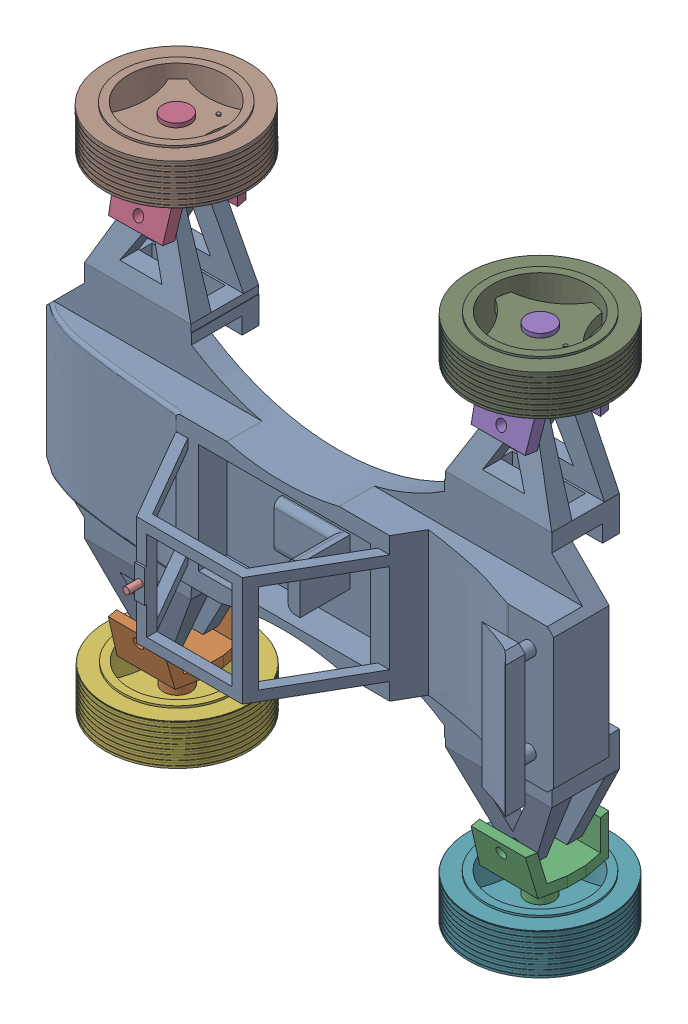
SolidWorks assembly car1, configuration Default. Lengths in mm.
Overall size (815.36 782.99 418.99).
10 component instances, 4 part files, 18 mates.
Components (placement in the parent):
- base-1: base [Default] at origin size (801.15 580 293)
- knuckle1-1: knuckle1 [Default] at (-218.0351 -285.881 -34.5) x (-0.999998 0.001925 0) z (0 0 1) size (100 120 120.94)
- knuckle1-2: knuckle1 [Default] at (317.973 -285.9418 -34.5) x (-0.999995 0.003142 0) z (0 0 1) size (100 120 120.94)
- knuckle1-3: knuckle1 [Default] at (-318.1763 285.0877 -34.5) x (0.999903 0.013919 0) z (0 0 1) size (100 120 120.94)
- knuckle1-4: knuckle1 [Default] at (218.0362 285.8852 -34.5) x (0.999998 -0.002009 0) z (0 0 1) size (100 120 120.94)
- wheel1-1: wheel1 [Default] at (-268.1733 -357.599 -30.0192) x (0.001925 0.999998 0) z (0 0 1) size (66 211.41 211.41)
- wheel1-2: wheel1 [Default] at (267.7476 -357.5987 -30.0192) x (0.003142 0.999995 0) z (0 0 1) size (66 211.41 211.41)
- wheel1-3: wheel1 [Default] at (-269.1808 357.591 -30.0192) x (0.013919 -0.999903 0) z (0 0 1) size (66 211.41 211.41)
- wheel1-4: wheel1 [Default] at (268.1804 357.599 -30.0192) x (-0.002009 -0.999998 0) z (-0.842947 0.001694 0.537993) size (66 211.41 211.41)
- lidar-1: lidar [Default] at (-70.5142 0.3632 223) size (10 10 20)
Mates (geometry in assembly coordinates):
- Coincident1: coincident anti-aligned: line of base-1 through (-268.0116 -273.5991 -16.3214) axis (0 0 1); line of knuckle1-1 through (-268.0116 -273.5991 29.5122) axis (0 0 -1)
- Coincident3: coincident anti-aligned: line of base-1 through (268.0116 -273.5991 -70) axis (0 0 1); line of knuckle1-2 through (268.0116 -273.5991 -74) axis (0 0 -1)
- Distance1: distance = 4 mm anti-aligned: plane of knuckle1-1 through (-318.0654 -301.5028 -74) normal (0 0 1); plane of base-1 through (0 0 -70) normal (0 0 -1)
- Distance2: distance = 4 mm anti-aligned: plane of base-1 through (0 0 -70) normal (0 0 -1); plane of knuckle1-2 through (217.9238 -301.4419 -74) normal (0 0 1)
- Coincident5: coincident anti-aligned: line of base-1 through (-268.0116 273.5991 -16.3214) axis (0 0 1); line of knuckle1-3 through (-268.0116 273.5991 29.5122) axis (0 0 -1)
- Distance3: distance = 4 mm anti-aligned: plane of base-1 through (0 0 -70) normal (0 0 -1); plane of knuckle1-3 through (-218.4061 302.2924 -74) normal (0 0 1)
- Coincident7: coincident anti-aligned: line of base-1 through (268.0116 273.5991 -16.3214) axis (0 0 1); line of knuckle1-4 through (268.0116 273.5991 -74) axis (0 0 -1)
- Distance6: distance = 4 mm anti-aligned: plane of knuckle1-4 through (318.0677 301.4986 -74) normal (0 0 1); plane of base-1 through (0 0 -70) normal (0 0 -1)
- Coincident13: coincident aligned: line of knuckle1-1 through (-268.2099 -376.5989 -30.0192) axis (0.001925 0.999998 0); line of wheel1-1 through (-268.1983 -370.599 -30.0192) axis (0.001925 0.999998 0)
- Distance8: distance = 6 mm aligned: plane of knuckle1-1 through (-268.2099 -376.5989 -30.0192) normal (-0.001925 -0.999998 0); plane of wheel1-1 through (-268.1983 -370.599 -30.0192) normal (-0.001925 -0.999998 0)
- Coincident17: coincident aligned: line of knuckle1-2 through (267.6879 -376.5986 -30.0192) axis (0.003142 0.999995 0); line of wheel1-2 through (267.7068 -370.5987 -30.0192) axis (0.003142 0.999995 0)
- Distance9: distance = 6 mm aligned: plane of wheel1-2 through (267.7068 -370.5987 -30.0192) normal (-0.003142 -0.999995 0); plane of knuckle1-2 through (267.6879 -376.5986 -30.0192) normal (-0.003142 -0.999995 0)
- Coincident19: coincident aligned: line of knuckle1-3 through (-269.4452 376.5892 -30.0192) axis (0.013919 -0.999903 0); line of wheel1-3 through (-269.3617 370.5897 -30.0192) axis (0.013919 -0.999903 0)
- Distance10: distance = 6 mm aligned: plane of wheel1-3 through (-269.3617 370.5897 -30.0192) normal (-0.013919 0.999903 0); plane of knuckle1-3 through (-269.4452 376.5892 -30.0192) normal (-0.013919 0.999903 0)
- Coincident23: coincident aligned: line of knuckle1-4 through (268.2185 376.5989 -30.0192) axis (-0.002009 -0.999998 0); line of wheel1-4 through (268.2065 370.5989 -30.0192) axis (-0.002009 -0.999998 0)
- Distance11: distance = 6 mm aligned: plane of wheel1-4 through (268.2065 370.5989 -30.0192) normal (0.002009 0.999998 0); plane of knuckle1-4 through (268.2185 376.5989 -30.0192) normal (0.002009 0.999998 0)
- Coincident25: coincident anti-aligned: plane of base-1 through (0 0 223) normal (0 0 1); plane of lidar-1 through (-70.5142 0.3632 223) normal (0 0 -1)
- Coincident27: coordinate: unknown of base-1
